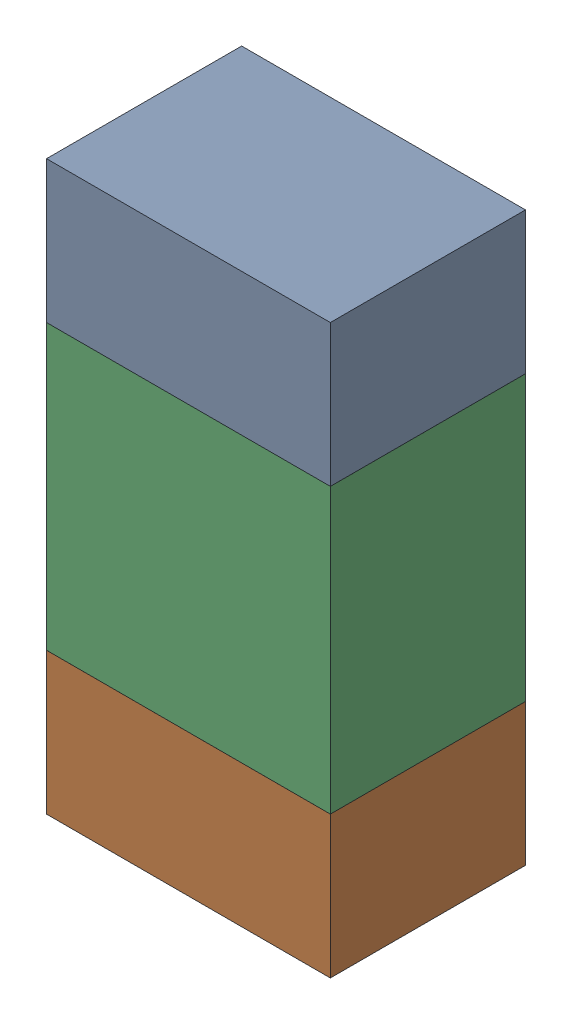
SolidWorks assembly R81, configuration ﾃﾞﾌｫﾙﾄ. Lengths in mm.
Overall size (0.8 1.6 0.55).
6 component instances, 2 part files, 0 mates.
Components (placement in the parent):
- 689261784-1: 689261784 [ﾃﾞﾌｫﾙﾄ] at (41.7501 65.5999 0) size (0.8 0.4 0.55)
  - Extruded_34-1: Extruded_34 [ﾃﾞﾌｫﾙﾄ] at origin size (0.8 0.4 0.55)
- 689261784-2: 689261784 [ﾃﾞﾌｫﾙﾄ] at (41.7501 64.3999 0) size (0.8 0.4 0.55)
  - Extruded_34-1: Extruded_34 [ﾃﾞﾌｫﾙﾄ] at origin size (0.8 0.4 0.55)
- 689261648-1: 689261648 [ﾃﾞﾌｫﾙﾄ] at (41.7501 65 0) size (0.8 0.8 0.55)
  - Extruded_33-1: Extruded_33 [ﾃﾞﾌｫﾙﾄ] at origin size (0.8 0.8 0.55)
